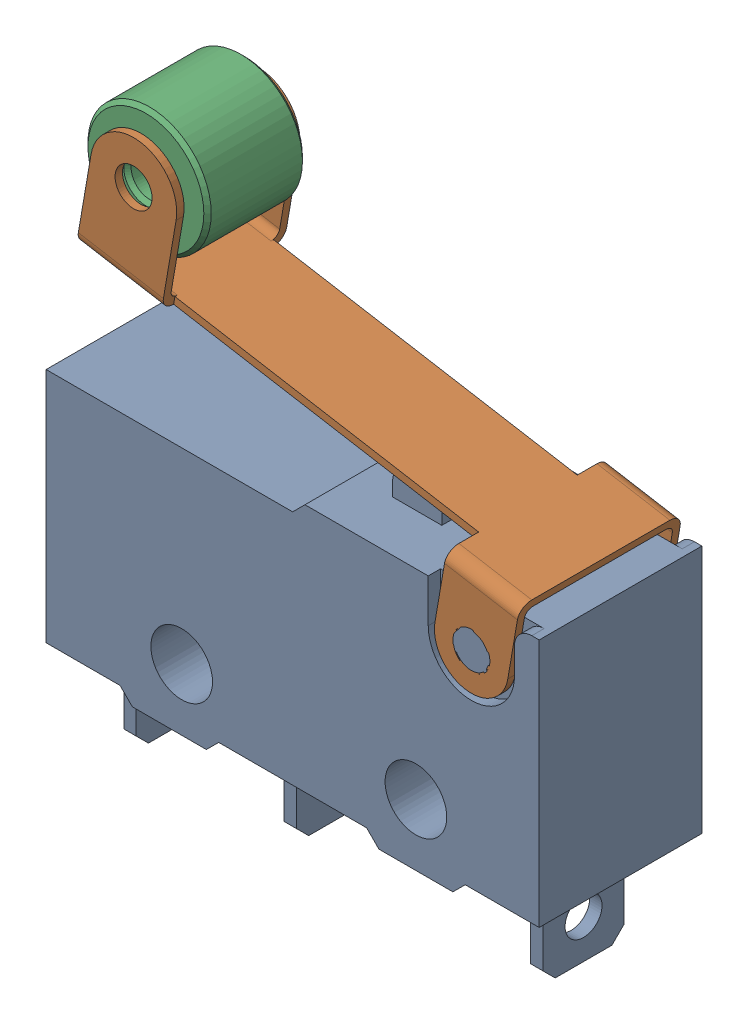
SolidWorks assembly Fin de carrera, configuration Default. Lengths in mm.
Overall size (20.3 23.07 6.6).
3 component instances, 3 part files, 5 mates.
Components (placement in the parent):
- Limit switch-1: Limit switch [Default] at (-5.6175 18.1081 17.0438) size (20 15.2 6.6)
- steel-1: steel [Default] at (13.5838 19.3646 18.3438) x (-0.985639 0.168868 0) z (0 0 1) size (19 9.3 6.6)
- roller-1: roller [Default] at (-2.8697 25.4809 18.3438) x (0 0 1) z (-1 0 0) size (4 5 5)
Mates (geometry in assembly coordinates):
- Width1: width aligned: plane of Limit switch-1 through (-5.6175 18.1081 17.0438) normal (0 0 -1); plane of steel-1 through (-5.6175 18.1081 23.6438) normal (0 0 1); plane of Limit switch-1 through (12.981 15.8463 17.0438) normal (0 0 -1); plane of steel-1 through (12.981 15.8463 23.6438) normal (0 0 1)
- Concentric1: concentric aligned: cylinder of Limit switch-1 through (11.6325 16.8581 25.7652) axis (0 0 -1) radius 0.75; cylinder of steel-1 through (11.6325 16.8581 23.6438) axis (0 0 -1) radius 0.7
- Concentric2: concentric anti-aligned: cylinder of steel-1 through (-2.8697 25.4809 17.0438) axis (0 0 1) radius 0.75; cylinder of roller-1 through (-2.8697 25.4809 22.3438) axis (0 0 -1) radius 0.75
- Width2: width anti-aligned: plane of steel-1 through (-0.8493 26.9102 18.1438) normal (0 0 1); plane of roller-1 through (-0.8493 26.9102 22.5438) normal (0 0 -1); plane of steel-1 through (-2.8697 25.4809 18.3438) normal (0 0 -1); plane of roller-1 through (-2.8697 25.4809 22.3438) normal (0 0 1)
- Tangent1: tangent anti-aligned: cylinder of Limit switch-1 through (7.3825 19.1081 21.5938) axis (0 0 1) radius 1; plane of steel-1 through (13.5331 19.0689 18.3438) normal (-0.168868 -0.985639 0)
